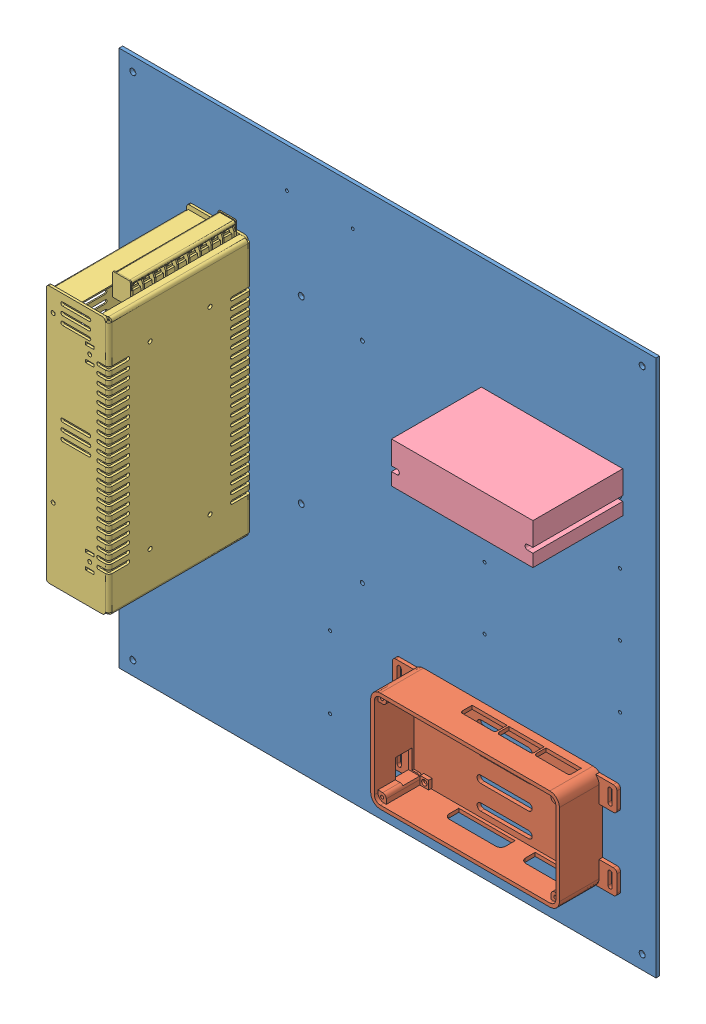
SolidWorks assembly Base_Assembly, configuration Default. Lengths in mm.
Overall size (448 448 122).
4 component instances, 4 part files, 7 mates.
Components (placement in the parent):
- BottomBase-1: BottomBase [Default] at origin size (448 448 3)
- Rumba Box-1: Rumba Box [Default] at (324.7309 84.9428 3) x (-1 0 0) z (0 0 1) size (187.5 84 36)
- Switching_Power_Supply-1: Switching_Power_Supply [Default] at (108.4 258.5 59.5) x (0 0 1) z (0 -1 0) size (119 52 226.5)
- DM542A MicrostepDriver-1: DM542A MicrostepDriver [Default] at (363.5837 337.1944 75) x (-1 0 0) z (0 0 -1) size (118 34 75)
Mates (geometry in assembly coordinates):
- Coincidente1: coincident anti-aligned: plane of BottomBase-1 through (0 0 0) normal (0 0 1); plane of Rumba Box-1 through (324.7309 84.9428 0) normal (0 0 -1)
- Parallelo1: parallel aligned: line of BottomBase-1 through (0 0 0) axis (1 0 0); line of Rumba Box-1 through (253.9809 42.9428 36) axis (1 0 0)
- Coincidente6: coincident anti-aligned: plane of BottomBase-1 through (0 0 0) normal (0 0 1); plane of DM542A MicrostepDriver-1 through (415.8337 332.6944 0) normal (0 0 -1)
- Parallelo2: parallel anti-aligned: line of BottomBase-1 through (448 448 0) axis (-1 0 0); line of DM542A MicrostepDriver-1 through (302.3337 354.1944 75) axis (1 0 0)
- Coincident1: coincident anti-aligned: plane of BottomBase-1 through (0 0 0) normal (0 0 1); plane of Switching_Power_Supply-1 through (109.6546 151 0) normal (0 0 -1)
- Concentric3: concentric anti-aligned: cylinder of BottomBase-1 through (70 333 -3) axis (0 0 1) radius 2.5; circle of Switching_Power_Supply-1
- Concentric5: concentric anti-aligned: cylinder of BottomBase-1 through (70 183 -3) axis (0 0 1) radius 2.5; circle of Switching_Power_Supply-1
